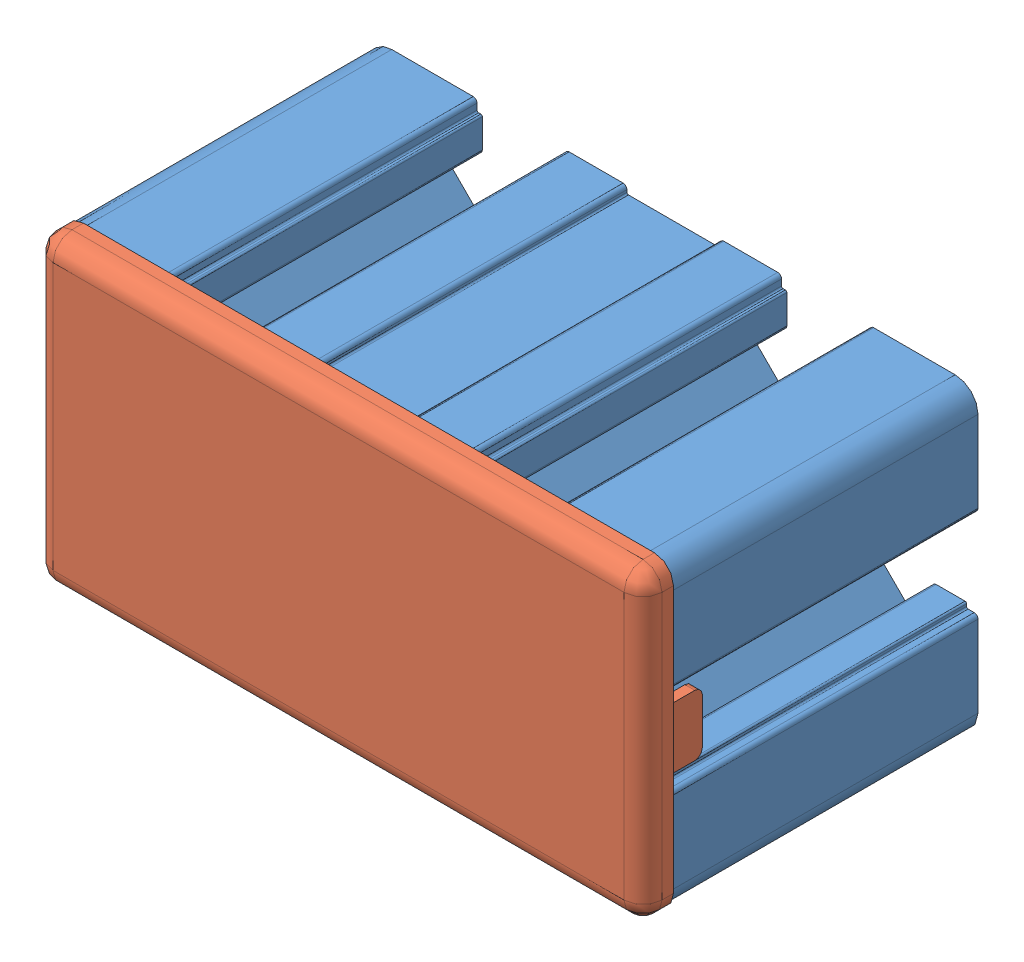
SolidWorks assembly Заглушка40х80СБ, configuration По умолчанию. Lengths in mm.
Overall size (80 40 44).
2 component instances, 2 part files, 6 mates.
Components (placement in the parent):
- 40х80 заглушка-1: 40х80 заглушка [По умолчанию] at origin size (80 40 40)
- Заглушка торцевая 40х80-1: Заглушка торцевая 40х80 [По умолчанию] at (20 0 42) x (0 0 -1) z (0 1 0) size (12.18 80 40)
Mates (geometry in assembly coordinates):
- Совпадение2: coincident: point of 40х80 заглушка-1
- Параллельность1: parallel anti-aligned: plane of 40х80 заглушка-1 through (0 -20 40) normal (0 -1 0)
- Совпадение4: coincident anti-aligned: plane of 40х80 заглушка-1 through (0 0 0) normal (0 0 -1)
- Совпадение5: coincident anti-aligned: plane of 40х80 заглушка-1 through (0 0 40) normal (0 0 1); plane of Заглушка торцевая 40х80-1 through (60 -20 40) normal (0 0 -1)
- Совпадение6: coincident aligned: plane of 40х80 заглушка-1 through (0 20 40) normal (0 1 0); plane of Заглушка торцевая 40х80-1 through (-17.5 20 41.5) normal (0 1 0)
- Совпадение7: coincident aligned: plane of 40х80 заглушка-1 through (60 0 40) normal (1 0 0); plane of Заглушка торцевая 40х80-1 through (60 -20 41.5) normal (1 0 0)
